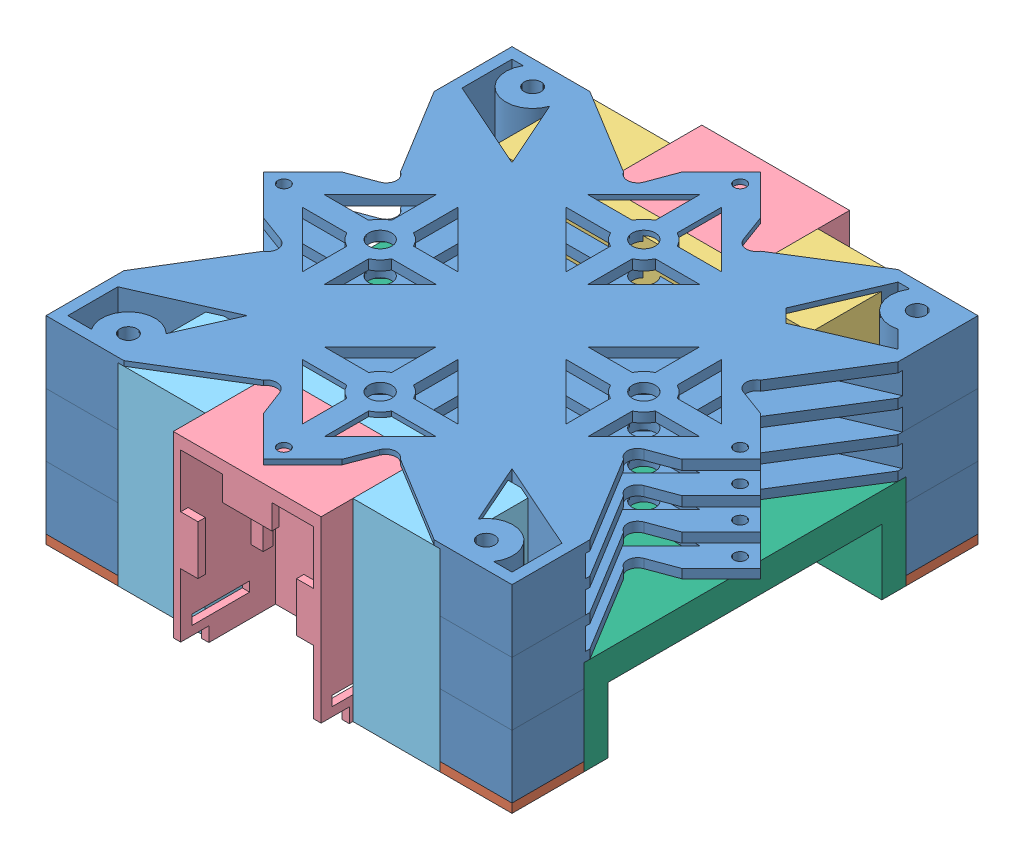
SolidWorks assembly BottomStart, configuration Default. Lengths in mm.
Overall size (102.59 40.85 109.22).
12 component instances, 9 part files, 41 mates.
Components (placement in the parent):
- 3dppart2-1: 3dppart2 [Default] at (-239.2395 19.4977 248.322) size (102.59 13 102.59)
- 3dppart2-2: 3dppart2 [Default] at (-239.2395 32.4977 248.322) size (102.59 13 102.59)
- 3dppart2-3: 3dppart2 [Default] at (-239.2395 45.4977 248.322) size (102.59 13 102.59)
- 3dprintpart-1: 3dprintpart [Default] at (-239.2395 6.6477 248.322) size (96.1 1.85 96.1)
- Part2^BottomStart-1: Part2^BottomStart [Default] at (-239.2395 47.4977 248.322) x (1 0 0) z (0 1 0) (virtual)
- Part3^BottomStart-1: Part3^BottomStart [Default] at (-239.2395 47.4977 248.322) x (1 0 0) z (0 1 0) (virtual)
- Part4^BottomStart-1: Part4^BottomStart [Default] at (-239.2395 47.4977 248.322) x (1 0 0) z (0 1 0) (virtual)
- BottomAntennaAttach1-1: BottomAntennaAttach1 [Default] at (-190.6614 26.5727 170.722) x (-1 0 0) z (0 0 -1) size (65.99 39.85 19.25)
- Base-1: Base [Default] at (-190.6614 21.0977 163.964) x (1 0 0) z (0 0 -1) size (30.48 39.85 20.83)
- Base-2: Base [Default] at (-190.4395 21.0977 235.08) x (-1 0 0) z (0 0 1) size (30.48 39.85 20.83)
- BottomAntennaAttach2-2: BottomAntennaAttach2 [Default] at (-190.4395 26.5727 228.322) size (66.44 39.85 19.25)
- GPSHolder-1: GPSHolder [Default] at (-190.4395 26.1477 199.522) x (-1 0 0) z (0 0 1) size (96.1 19.5 66.44)
Mates (geometry in assembly coordinates):
- Coincident1: coincident aligned: plane of 3dppart2-3 through (-239.2395 45.4977 247.572) normal (0 0 1); plane of 3dppart2-2 through (-239.2395 32.4977 247.572) normal (0 0 1)
- Coincident2: coincident aligned: plane of 3dppart2-1 through (-239.2395 19.4977 247.572) normal (0 0 1); plane of 3dppart2-3 through (-239.2395 45.4977 247.572) normal (0 0 1)
- Coincident3: coincident anti-aligned: plane of 3dppart2-2 through (-239.2395 34.4977 248.322) normal (0 1 0); plane of 3dppart2-3 through (-239.2395 34.4977 248.322) normal (0 -1 0)
- Coincident4: coincident anti-aligned: plane of 3dppart2-1 through (-239.2395 21.4977 248.322) normal (0 1 0); plane of 3dppart2-2 through (-239.2395 21.4977 248.322) normal (0 -1 0)
- Coincident5: coincident aligned: plane of 3dppart2-3 through (-142.3895 45.4977 248.322) normal (1 0 0); plane of 3dppart2-2 through (-142.3895 32.4977 248.322) normal (1 0 0)
- Coincident6: coincident aligned: plane of 3dppart2-1 through (-142.3895 19.4977 248.322) normal (1 0 0); plane of 3dppart2-3 through (-142.3895 45.4977 248.322) normal (1 0 0)
- Coincident7: coincident anti-aligned: plane of 3dppart2-1 through (-239.2395 8.4977 248.322) normal (0 -1 0); plane of 3dprintpart-1 through (-239.2395 8.4977 248.322) normal (0 1 0)
- Coincident8: coincident aligned: plane of 3dppart2-1 through (-239.2395 19.4977 247.572) normal (0 0 1); plane of 3dprintpart-1 through (-239.2395 6.6477 247.572) normal (0 0 1)
- Coincident9: coincident aligned: plane of 3dppart2-1 through (-142.3895 19.4977 248.322) normal (1 0 0); plane of 3dprintpart-1 through (-142.3895 6.6477 248.322) normal (1 0 0)
- InPlace1: in place: plane of 3dppart2-3 through (-239.2395 47.4977 248.322) normal (0 1 0); plane of ? through (0 47.4977 0) normal (0 1 0); moOrthogonalPlaneRef_w of 3dppart2-3 through (-239.2395 47.4977 248.322) normal (0 1 0); plane of ? through (0 47.4977 0) normal (0 0 -1); plane of 3dppart2-3 through (-239.2395 47.4977 248.322) normal (0 1 0); line of ? through (-55 0 47.4977) axis (0 1 0); plane of 3dppart2-3 through (-239.2395 47.4977 248.322) normal (0 1 0); unknown of ?
- Coincident10: coincident aligned: plane of 3dppart2-3; plane of Part2^BottomStart-1
- Coincident11: coincident aligned: moOrthogonalPlaneRef_w of 3dppart2-3 through (-239.2395 47.4977 248.322) normal (0 0 -1); plane of Part2^BottomStart-1 through (-239.2395 47.4977 248.322) normal (0 0 -1)
- Coincident12: coincident anti-aligned: moOrthogonalPlaneRef_w of 3dppart2-3 through (-239.2395 47.4977 248.322) normal (-1 0 0); plane of Part2^BottomStart-1
- InPlace2: in place: plane of 3dppart2-3 through (-239.2395 47.4977 248.322) normal (0 1 0); plane of ? through (0 47.4977 0) normal (0 1 0); plane of 3dppart2-3 through (-239.2395 47.4977 248.322) normal (0 1 0); plane of ? through (0 47.4977 0) normal (0 0 -1); plane of 3dppart2-3 through (-239.2395 47.4977 248.322) normal (0 1 0); line of ? through (-55 0 47.4977) axis (0 1 0); plane of 3dppart2-3 through (-239.2395 47.4977 248.322) normal (0 1 0); unknown of ?
- Coincident13: coincident aligned: plane of 3dppart2-3; plane of Part3^BottomStart-1
- Coincident14: coincident aligned: moOrthogonalPlaneRef_w of 3dppart2-3 through (-239.2395 47.4977 248.322) normal (0 0 -1); plane of Part3^BottomStart-1 through (-239.2395 47.4977 248.322) normal (0 0 -1)
- Coincident15: coincident anti-aligned: moOrthogonalPlaneRef_w of 3dppart2-3 through (-239.2395 47.4977 248.322) normal (-1 0 0); plane of Part3^BottomStart-1
- InPlace3: in place: plane of 3dppart2-3 through (-239.2395 47.4977 248.322) normal (0 1 0); plane of ? through (0 47.4977 0) normal (0 1 0); plane of 3dppart2-3 through (-239.2395 47.4977 248.322) normal (0 1 0); plane of ? through (0 47.4977 0) normal (0 0 -1); plane of 3dppart2-3 through (-239.2395 47.4977 248.322) normal (0 1 0); line of ? through (-55 0 47.4977) axis (0 1 0); plane of 3dppart2-3 through (-239.2395 47.4977 248.322) normal (0 1 0); unknown of ?
- Coincident16: coincident aligned: plane of 3dppart2-3; plane of Part4^BottomStart-1
- Coincident17: coincident aligned: moOrthogonalPlaneRef_w of 3dppart2-3 through (-239.2395 47.4977 248.322) normal (0 0 -1); plane of Part4^BottomStart-1 through (-239.2395 47.4977 248.322) normal (0 0 -1)
- Coincident18: coincident anti-aligned: moOrthogonalPlaneRef_w of 3dppart2-3 through (-239.2395 47.4977 248.322) normal (-1 0 0); plane of Part4^BottomStart-1
- Coincident10: coincident anti-aligned: plane of 3dppart2-1 through (-157.6645 45.4977 170.722) normal (-1 0 0); plane of BottomAntennaAttach1-1 through (-157.6645 46.4977 150.722) normal (1 0 0)
- Coincident11: coincident anti-aligned: plane of 3dppart2-1 through (-223.6583 45.4977 170.722) normal (1 0 0); plane of BottomAntennaAttach1-1 through (-223.6583 46.4977 150.722) normal (-1 0 0)
- Coincident12: coincident anti-aligned: plane of 3dppart2-3 through (0 46.4977 0) normal (0 -1 0); plane of BottomAntennaAttach1-1 through (-223.6583 46.4977 150.722) normal (0 1 0)
- Coincident18: coincident anti-aligned: plane of 3dppart2-2 through (-157.2208 45.4977 228.322) normal (-1 0 0); plane of BottomAntennaAttach2-2 through (-157.2208 46.4977 248.322) normal (1 0 0)
- Coincident21: coincident anti-aligned: plane of 3dppart2-2 through (-223.6583 45.4977 228.322) normal (1 0 0); plane of BottomAntennaAttach2-2 through (-223.6583 46.4977 248.322) normal (-1 0 0)
- Coincident22: coincident anti-aligned: plane of 3dppart2-3 through (0 46.4977 0) normal (0 -1 0); plane of BottomAntennaAttach2-2 through (-157.2208 46.4977 248.322) normal (0 1 0)
- Coincident23: coincident anti-aligned: plane of 3dppart2-2 through (0 0 228.322) normal (0 0 1); plane of BottomAntennaAttach2-2 through (-190.4395 26.5727 228.322) normal (0 0 -1)
- Coincident24: coincident anti-aligned: plane of Base-2 through (-205.6795 46.4977 233.302) normal (-1 0 0); plane of BottomAntennaAttach2-2 through (-205.6795 46.4977 233.302) normal (1 0 0)
- Coincident25: coincident anti-aligned: plane of 3dppart2-3 through (0 46.4977 0) normal (0 -1 0); plane of Base-2 through (-205.6795 46.4977 233.302) normal (0 1 0)
- Coincident26: coincident anti-aligned: plane of Base-2 through (-175.1995 46.4977 233.302) normal (1 0 0); plane of BottomAntennaAttach2-2 through (-175.1995 46.4977 233.302) normal (-1 0 0)
- Coincident27: coincident anti-aligned: plane of Base-2 through (-190.4395 21.0977 233.302) normal (0 0 -1); plane of BottomAntennaAttach2-2 through (-190.4395 26.5727 233.302) normal (0 0 1)
- Coincident28: coincident anti-aligned: plane of BottomAntennaAttach1-1 through (-205.9014 46.4977 165.742) normal (1 0 0); plane of Base-1 through (-205.9014 46.4977 165.742) normal (-1 0 0)
- Coincident29: coincident anti-aligned: plane of BottomAntennaAttach1-1 through (-190.6614 26.5727 165.742) normal (0 0 -1); plane of Base-1 through (-190.6614 21.0977 165.742) normal (0 0 1)
- Coincident30: coincident anti-aligned: plane of BottomAntennaAttach1-1 through (-175.4214 46.4977 165.742) normal (-1 0 0); plane of Base-1 through (-175.4214 46.4977 165.742) normal (1 0 0)
- Coincident31: coincident anti-aligned: plane of 3dppart2-3 through (0 46.4977 0) normal (0 -1 0); plane of Base-1 through (-175.4214 46.4977 165.742) normal (0 1 0)
- Lock1: lock: unknown of 3dprintpart-1; unknown of BottomAntennaAttach1-1
- Lock2: lock: unknown of 3dprintpart-1; unknown of BottomAntennaAttach2-2
- Coincident32: coincident anti-aligned: plane of 3dppart2-2 through (0 26.1477 0) normal (0 -1 0); plane of GPSHolder-1 through (-190.4395 26.1477 199.522) normal (0 1 0)
- Coincident33: coincident aligned: plane of 3dppart2-1 through (-238.4895 19.4977 248.322) normal (-1 0 0); plane of GPSHolder-1 through (-238.4895 26.1477 199.522) normal (-1 0 0)
- Coincident34: coincident anti-aligned: plane of BottomAntennaAttach2-2 through (0 26.1477 232.7408) normal (0 0 -1); plane of GPSHolder-1 through (-239.2395 20.1477 232.7408) normal (0 0 1)
